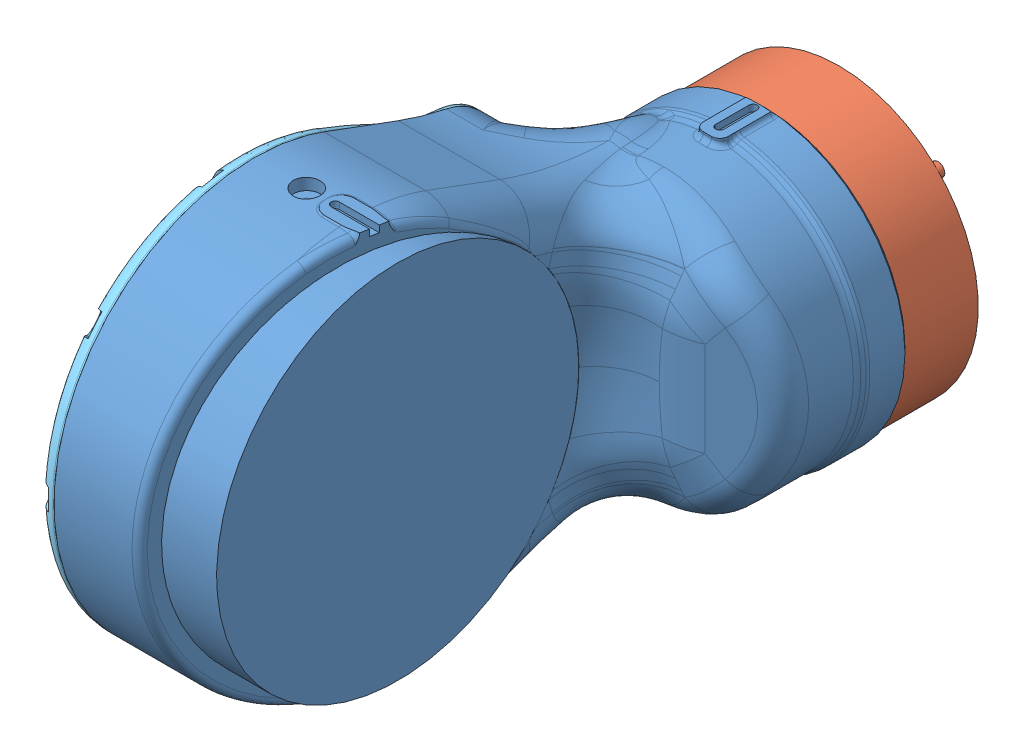
SolidWorks assembly ASM-L__ASM, configuration Valor predeterminado. Lengths in mm.
Overall size (205.83 242.14 386.25).
5 component instances, 5 part files, 0 mates.
Components (placement in the parent):
- L_ARM_A_CAST_-1: L_ARM_A_CAST_ [Valor predeterminado] at (0 0 -215.5) x (0 1 0) z (1 0 0) size (242.14 335.85 180.31)
- AC32_-1: AC32_ [Valor predeterminado] at (0 0 -215.5) x (0 1 0) z (0 0 1) size (167 167 121.2)
- 0411564_1_-1: 0411564_1_ [Valor predeterminado] at (0 0 -152.1) x (0 0 -1) z (0 1 0) size (111 71 71)
- 0411584_1_-1: 0411584_1_ [Valor predeterminado] at (-94.0749 0 0) size (12 115 115)
- L_A_COVER_-1: L_A_COVER_ [Valor predeterminado] at (-91 0 0) x (0 -1 0) z (-1 0 0) size (240 267.04 33.35)
